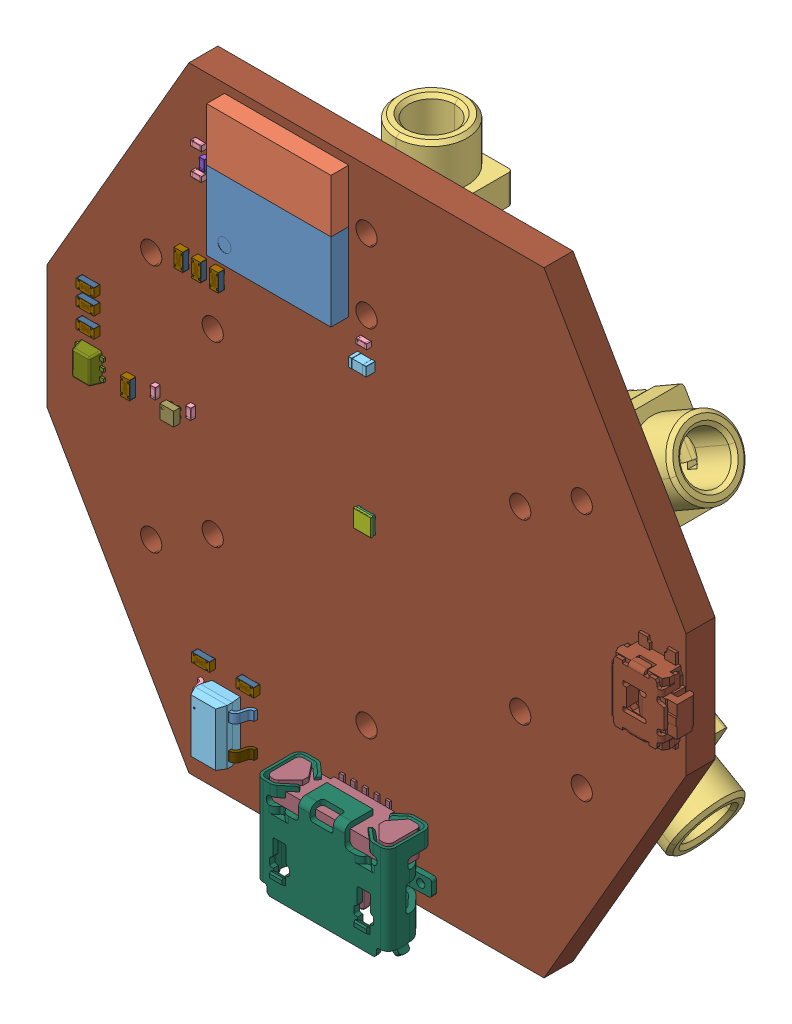
SolidWorks assembly Planter, configuration Default. Lengths in mm.
Overall size (36.62 36.63 8.42).
164 component instances, 47 part files, 0 mates.
Components (placement in the parent):
- U2-1: U2 [Default] at origin size (7 7.4 1)
  - U2-subassembly-1-1: U2-subassembly-1 [Default] at (-4.5 13.125 0) x (1 0 0) z (0 -1 0) size (7 1 7.4)
    - Murata MBN52832-1: Murata MBN52832 [Default] at origin size (7 1 4.4)
    - Murata MBN52832-1-1: Murata MBN52832-1 [Default] at origin size (7 1 3)
- J1-1: J1 [Default] at origin size (7.4 12.56 4.5)
  - CUI_DEVICES_SJ2-25103A-SMT-TR-1: CUI_DEVICES_SJ2-25103A-SMT-TR [Default] at (-0.2901 12.0599 -1.7307) x (0 1 0) z (0 0 -1) size (12.56 7.4 4.5)
- J3-1: J3 [Default] at origin size (14.57 12.69 4.5)
  - CUI_DEVICES_SJ2-25103A-SMT-TR-1: CUI_DEVICES_SJ2-25103A-SMT-TR [Default] at (10.5892 -5.7787 -1.7307) x (0.866025 -0.5 0) z (0 0 -1) size (12.56 7.4 4.5)
- J4-1: J4 [Default] at origin size (7.4 12.56 4.5)
  - CUI_DEVICES_SJ2-25103A-SMT-TR-1: CUI_DEVICES_SJ2-25103A-SMT-TR [Default] at (0.2901 -12.0599 -1.7307) x (0 -1 0) z (0 0 -1) size (12.56 7.4 4.5)
- J5-1: J5 [Default] at origin size (14.57 12.69 4.5)
  - CUI_DEVICES_SJ2-25103A-SMT-TR-1: CUI_DEVICES_SJ2-25103A-SMT-TR [Default] at (-10.2991 -6.2812 -1.7307) x (-0.866025 -0.5 0) z (0 0 -1) size (12.56 7.4 4.5)
- J6-1: J6 [Default] at origin size (14.57 12.69 4.5)
  - CUI_DEVICES_SJ2-25103A-SMT-TR-1: CUI_DEVICES_SJ2-25103A-SMT-TR [Default] at (-10.5892 5.7787 -1.7307) x (-0.866025 0.5 0) z (0 0 -1) size (12.56 7.4 4.5)
- C1-1: C1 [Default] at origin size (0.53 0.7 0.46)
  - CAP 0201-1: CAP 0201 [Default] at (-9.7499 0.5099 0) x (1 0 0) z (0 -1 0) size (0.53 0.46 0.7)
- C2-1: C2 [Default] at origin size (0.53 0.7 0.46)
  - CAP 0201-1: CAP 0201 [Default] at (-11.7499 0.5099 0) x (1 0 0) z (0 -1 0) size (0.53 0.46 0.7)
- C3-1: C3 [Default] at origin size (0.7 0.53 0.46)
  - CAP 0201-1: CAP 0201 [Default] at (-9.3101 12.2499 0) x (0 -1 0) z (-1 0 0) size (0.53 0.46 0.7)
- C4-1: C4 [Default] at origin size (0.7 0.53 0.46)
  - CAP 0201-1: CAP 0201 [Default] at (-9.3101 13.7499 0) x (0 -1 0) z (-1 0 0) size (0.53 0.46 0.7)
- C5-1: C5 [Default] at origin size (1 0.52 0.52)
  - 0402 cap-1: 0402 cap [Default] at (-0.0001 7.7499 0) x (-1 0 0) z (0 1 0) size (1 0.52 0.52)
- C6-1: C6 [Default] at origin size (0.7 0.53 0.46)
  - CAP 0201-1: CAP 0201 [Default] at (-0.0001 8.7499 0) x (0 -1 0) z (-1 0 0) size (0.53 0.46 0.7)
- D1-1: D1 [Default] at origin size (1.01 1.01 0.26)
  - LUMEX 0404 Base RGB-1: LUMEX 0404 Base RGB [Default] x (0 -1 0) z (0 0 1) size (1.01 1.01 0.15)
  - LUMEX 0404 Lens RGB-1: LUMEX 0404 Lens RGB [Default] at (0 0 0) x (0 -1 0) z (0 0 1) size (1 1 0.12)
- J2-1: J2 [Default] at origin size (14.57 12.69 4.5)
  - CUI_DEVICES_SJ2-25103A-SMT-TR-1: CUI_DEVICES_SJ2-25103A-SMT-TR [Default] at (10.2991 6.2812 -1.7307) x (0.866025 0.5 0) z (0 0 -1) size (12.56 7.4 4.5)
- L1-1: L1 [Default] at origin size (0.53 0.7 0.46)
  - FER 0201-1: FER 0201 [Default] at (-9 13.0001 -0.01) x (1 0 0) z (0 -1 0) size (0.53 0.46 0.7)
- R5-1: R5 [Default] at origin size (1 0.5 0.35)
  - R5-subassembly-1-1: R5-subassembly-1 [Default] at (-6.5001 -11 0) x (1 0 0) z (0 -1 0) size (1 0.35 0.5)
    - 0402 resistor-1: 0402 resistor [Default] at origin size (1 0.35 0.5)
    - 0402 resistor-1-1: 0402 resistor-1 [Default] at origin size (0.96 0.31 0.5)
- R6-1: R6 [Default] at origin size (0.5 1 0.35)
  - R6-subassembly-1-1: R6-subassembly-1 [Default] at (-9.5 7.7499 0) x (0 1 0) z (1 0 0) size (1 0.35 0.5)
    - 0402 resistor-1: 0402 resistor [Default] at origin size (1 0.35 0.5)
    - 0402 resistor-1-1: 0402 resistor-1 [Default] at origin size (0.96 0.31 0.5)
- R7-1: R7 [Default] at origin size (0.5 1 0.35)
  - R7-subassembly-1-1: R7-subassembly-1 [Default] at (-8.5 7.7499 0) x (0 1 0) z (1 0 0) size (1 0.35 0.5)
    - 0402 resistor-1: 0402 resistor [Default] at origin size (1 0.35 0.5)
    - 0402 resistor-1-1: 0402 resistor-1 [Default] at origin size (0.96 0.31 0.5)
- S1-1: S1 [Default] at origin size (3.55 4.7 1.35)
  - User Library-EVQP7-JA-01P-1: User Library-EVQP7-JA-01P [Default] at (16.5128 0.0268 0) x (0 1 0) z (1 0 0) size (4.7 1.35 3.55)
- U1-1: U1 [Default] at origin size (0.77 0.77 0.56)
  - ST flip-chip4-1: ST flip-chip4 [Default] at (-10.75 0 0) x (0 -1 0) z (-1 0 0) size (0.77 0.56 0.77)
- J7-1: J7 [Default] at origin size (7.92 5.67 3.01)
  - Amphenol 10118192-1: Amphenol 10118192 [Default] at (-97.9992 -12.7205 -0.35) x (1 0 0) z (0 -1 0) size (7.92 3.01 5.67)
    - unnamed-1: unnamed [Default] at origin size (6.89 2.28 4.27)
    - unnamed-1-1: unnamed-1 [Default] at origin size (0 0.01 0)
    - unnamed-2-1: unnamed-2 [Default] at origin size (7.92 3.01 5.67)
- Q1-1: Q1 [Default] at origin size (1.6 1.6 0.6)
  - Diodes SOT-563-1: Diodes SOT-563 [Default] at (-15.5 0 0) x (0 1 0) z (0 0 1) size (1.6 1.6 0.6)
- R1-1: R1 [Default] at origin size (0.5 1 0.35)
  - R1-subassembly-1-1: R1-subassembly-1 [Default] at (-13 0.0001 0) x (0 -1 0) z (-1 0 0) size (1 0.35 0.5)
    - 0402 resistor-1: 0402 resistor [Default] at origin size (1 0.35 0.5)
    - 0402 resistor-1-1: 0402 resistor-1 [Default] at origin size (0.96 0.31 0.5)
- R2-1: R2 [Default] at origin size (1 0.5 0.35)
  - R2-subassembly-1-1: R2-subassembly-1 [Default] at (-15.4999 2.625 0) x (-1 0 0) z (0 1 0) size (1 0.35 0.5)
    - 0402 resistor-1: 0402 resistor [Default] at origin size (1 0.35 0.5)
    - 0402 resistor-1-1: 0402 resistor-1 [Default] at origin size (0.96 0.31 0.5)
- R3-1: R3 [Default] at origin size (1 0.5 0.35)
  - R3-subassembly-1-1: R3-subassembly-1 [Default] at (-15.4999 1.5 0) x (-1 0 0) z (0 1 0) size (1 0.35 0.5)
    - 0402 resistor-1: 0402 resistor [Default] at origin size (1 0.35 0.5)
    - 0402 resistor-1-1: 0402 resistor-1 [Default] at origin size (0.96 0.31 0.5)
- R4-1: R4 [Default] at origin size (1 0.5 0.35)
  - R4-subassembly-1-1: R4-subassembly-1 [Default] at (-15.5001 4 0) x (1 0 0) z (0 -1 0) size (1 0.35 0.5)
    - 0402 resistor-1: 0402 resistor [Default] at origin size (1 0.35 0.5)
    - 0402 resistor-1-1: 0402 resistor-1 [Default] at origin size (0.96 0.31 0.5)
- R8-1: R8 [Default] at origin size (0.5 1 0.35)
  - R8-subassembly-1-1: R8-subassembly-1 [Default] at (-10.5 7.7499 0) x (0 1 0) z (1 0 0) size (1 0.35 0.5)
    - 0402 resistor-1: 0402 resistor [Default] at origin size (1 0.35 0.5)
    - 0402 resistor-1-1: 0402 resistor-1 [Default] at origin size (0.96 0.31 0.5)
- R9-1: R9 [Default] at origin size (1 0.5 0.35)
  - R9-subassembly-1-1: R9-subassembly-1 [Default] at (-9.0001 -11 0) x (1 0 0) z (0 -1 0) size (1 0.35 0.5)
    - 0402 resistor-1: 0402 resistor [Default] at origin size (1 0.35 0.5)
    - 0402 resistor-1-1: 0402 resistor-1 [Default] at origin size (0.96 0.31 0.5)
- U3-1: U3 [Default] at origin size (3.2 3.11 1.46)
  - U3-subassembly-1-1: U3-subassembly-1 [Default] at (-7.75 -13.5 0) x (1 0 0) z (0 0 1) size (3.2 3.11 1.46)
    - Microchip SOT-23-5-1: Microchip SOT-23-5 [Default] at origin size (0.11 0.11 0.02)
    - Microchip SOT-23-5-1-1: Microchip SOT-23-5-1 [Default] at origin size (0.7 0.51 0.93)
    - Microchip SOT-23-5-2-1: Microchip SOT-23-5-2 [Default] at origin size (0.7 0.51 0.93)
    - Microchip SOT-23-5-3-1: Microchip SOT-23-5-3 [Default] at origin size (0.7 0.51 0.93)
    - Microchip SOT-23-5-4-1: Microchip SOT-23-5-4 [Default] at origin size (0.7 0.51 0.93)
    - Microchip SOT-23-5-5-1: Microchip SOT-23-5-5 [Default] at origin size (0.7 0.51 0.93)
    - Microchip SOT-23-5-6-1: Microchip SOT-23-5-6 [Default] at origin size (1.81 3.11 1.3)
- R10-1: R10 [Default] at origin size (0.93 1.12 0.35)
  - R10-subassembly-1-1: R10-subassembly-1 [Default] at (-4.2164 4.125 -1.6307) x (-0.5 -0.866025 0) z (0.866025 -0.5 0) size (1 0.35 0.5)
    - 0402 resistor-1: 0402 resistor [Default] at origin size (1 0.35 0.5)
    - 0402 resistor-1-1: 0402 resistor-1 [Default] at origin size (0.96 0.31 0.5)
- R11-1: R11 [Default] at origin size (0.93 1.12 0.35)
  - R11-subassembly-1-1: R11-subassembly-1 [Default] at (-5.2836 1.375 -1.6307) x (0.5 0.866025 0) z (-0.866025 0.5 0) size (1 0.35 0.5)
    - 0402 resistor-1: 0402 resistor [Default] at origin size (1 0.35 0.5)
    - 0402 resistor-1-1: 0402 resistor-1 [Default] at origin size (0.96 0.31 0.5)
- R12-1: R12 [Default] at origin size (0.93 1.12 0.35)
  - R12-subassembly-1-1: R12-subassembly-1 [Default] at (-5.679 -1.6229 -1.6307) x (0.5 -0.866025 0) z (0.866025 0.5 0) size (1 0.35 0.5)
    - 0402 resistor-1: 0402 resistor [Default] at origin size (1 0.35 0.5)
    - 0402 resistor-1-1: 0402 resistor-1 [Default] at origin size (0.96 0.31 0.5)
- R13-1: R13 [Default] at origin size (0.93 1.12 0.35)
  - R13-subassembly-1-1: R13-subassembly-1 [Default] at (-3.821 -3.8771 -1.6307) x (-0.5 0.866025 0) z (-0.866025 -0.5 0) size (1 0.35 0.5)
    - 0402 resistor-1: 0402 resistor [Default] at origin size (1 0.35 0.5)
    - 0402 resistor-1-1: 0402 resistor-1 [Default] at origin size (0.96 0.31 0.5)
- R14-1: R14 [Default] at origin size (1 0.5 0.35)
  - R14-subassembly-1-1: R14-subassembly-1 [Default] at (-1.4251 -5.7499 -1.6307) x (1 0 0) z (0 1 0) size (1 0.35 0.5)
    - 0402 resistor-1: 0402 resistor [Default] at origin size (1 0.35 0.5)
    - 0402 resistor-1-1: 0402 resistor-1 [Default] at origin size (0.96 0.31 0.5)
- R15-1: R15 [Default] at origin size (1 0.5 0.35)
  - R15-subassembly-1-1: R15-subassembly-1 [Default] at (1.4251 -5.25 -1.6307) x (-1 0 0) z (0 -1 0) size (1 0.35 0.5)
    - 0402 resistor-1: 0402 resistor [Default] at origin size (1 0.35 0.5)
    - 0402 resistor-1-1: 0402 resistor-1 [Default] at origin size (0.96 0.31 0.5)
- R16-1: R16 [Default] at origin size (0.93 1.12 0.35)
  - R16-subassembly-1-1: R16-subassembly-1 [Default] at (4.2539 -4.1271 -1.6307) x (0.5 0.866025 0) z (-0.866025 0.5 0) size (1 0.35 0.5)
    - 0402 resistor-1: 0402 resistor [Default] at origin size (1 0.35 0.5)
    - 0402 resistor-1-1: 0402 resistor-1 [Default] at origin size (0.96 0.31 0.5)
- R17-1: R17 [Default] at origin size (0.93 1.12 0.35)
  - R17-subassembly-1-1: R17-subassembly-1 [Default] at (5.2461 -1.3729 -1.6307) x (-0.5 -0.866025 0) z (0.866025 -0.5 0) size (1 0.35 0.5)
    - 0402 resistor-1: 0402 resistor [Default] at origin size (1 0.35 0.5)
    - 0402 resistor-1-1: 0402 resistor-1 [Default] at origin size (0.96 0.31 0.5)
- R18-1: R18 [Default] at origin size (0.93 1.12 0.35)
  - R18-subassembly-1-1: R18-subassembly-1 [Default] at (5.679 1.6229 -1.6307) x (-0.5 0.866025 0) z (-0.866025 -0.5 0) size (1 0.35 0.5)
    - 0402 resistor-1: 0402 resistor [Default] at origin size (1 0.35 0.5)
    - 0402 resistor-1-1: 0402 resistor-1 [Default] at origin size (0.96 0.31 0.5)
- R19-1: R19 [Default] at origin size (0.93 1.12 0.35)
  - R19-subassembly-1-1: R19-subassembly-1 [Default] at (3.821 3.8771 -1.6307) x (0.5 -0.866025 0) z (0.866025 0.5 0) size (1 0.35 0.5)
    - 0402 resistor-1: 0402 resistor [Default] at origin size (1 0.35 0.5)
    - 0402 resistor-1-1: 0402 resistor-1 [Default] at origin size (0.96 0.31 0.5)
- R20-1: R20 [Default] at origin size (1 0.5 0.35)
  - R20-subassembly-1-1: R20-subassembly-1 [Default] at (1.4251 5.75 -1.6307) x (-1 0 0) z (0 -1 0) size (1 0.35 0.5)
    - 0402 resistor-1: 0402 resistor [Default] at origin size (1 0.35 0.5)
    - 0402 resistor-1-1: 0402 resistor-1 [Default] at origin size (0.96 0.31 0.5)
- R21-1: R21 [Default] at origin size (1 0.5 0.35)
  - R21-subassembly-1-1: R21-subassembly-1 [Default] at (-1.4251 5.25 -1.6307) x (1 0 0) z (0 1 0) size (1 0.35 0.5)
    - 0402 resistor-1: 0402 resistor [Default] at origin size (1 0.35 0.5)
    - 0402 resistor-1-1: 0402 resistor-1 [Default] at origin size (0.96 0.31 0.5)
- U4-1: U4 [Default] at origin size (3.1 3.1 0.84)
  - U4-subassembly-1-1: U4-subassembly-1 [Default] at (0.0001 0 -1.6307) x (0 1 0) z (0 0 -1) size (3.1 3.1 0.84)
    - VQFN20_3X3_MCH-1: VQFN20_3X3_MCH [Default] at origin size (1.7 1.7 0.05)
    - VQFN20_3X3_MCH-1-1: VQFN20_3X3_MCH-1 [Default] at origin size (0.28 0.41 0.05)
    - VQFN20_3X3_MCH-2-1: VQFN20_3X3_MCH-2 [Default] at origin size (0.28 0.41 0.05)
    - VQFN20_3X3_MCH-3-1: VQFN20_3X3_MCH-3 [Default] at origin size (0.28 0.41 0.05)
    - VQFN20_3X3_MCH-4-1: VQFN20_3X3_MCH-4 [Default] at origin size (0.28 0.41 0.05)
    - VQFN20_3X3_MCH-5-1: VQFN20_3X3_MCH-5 [Default] at origin size (0.28 0.41 0.05)
    - VQFN20_3X3_MCH-6-1: VQFN20_3X3_MCH-6 [Default] at origin size (0.41 0.28 0.05)
    - VQFN20_3X3_MCH-7-1: VQFN20_3X3_MCH-7 [Default] at origin size (0.41 0.28 0.05)
    - VQFN20_3X3_MCH-8-1: VQFN20_3X3_MCH-8 [Default] at origin size (0.41 0.28 0.05)
    - VQFN20_3X3_MCH-9-1: VQFN20_3X3_MCH-9 [Default] at origin size (0.41 0.28 0.05)
    - VQFN20_3X3_MCH-10-1: VQFN20_3X3_MCH-10 [Default] at origin size (0.41 0.28 0.05)
    - VQFN20_3X3_MCH-11-1: VQFN20_3X3_MCH-11 [Default] at origin size (0.28 0.41 0.05)
    - VQFN20_3X3_MCH-12-1: VQFN20_3X3_MCH-12 [Default] at origin size (0.28 0.41 0.05)
    - VQFN20_3X3_MCH-13-1: VQFN20_3X3_MCH-13 [Default] at origin size (0.28 0.41 0.05)
    - VQFN20_3X3_MCH-14-1: VQFN20_3X3_MCH-14 [Default] at origin size (0.28 0.41 0.05)
    - VQFN20_3X3_MCH-15-1: VQFN20_3X3_MCH-15 [Default] at origin size (0.28 0.41 0.05)
    - VQFN20_3X3_MCH-16-1: VQFN20_3X3_MCH-16 [Default] at origin size (0.41 0.28 0.05)
    - VQFN20_3X3_MCH-17-1: VQFN20_3X3_MCH-17 [Default] at origin size (0.41 0.28 0.05)
    - VQFN20_3X3_MCH-18-1: VQFN20_3X3_MCH-18 [Default] at origin size (0.41 0.28 0.05)
    - VQFN20_3X3_MCH-19-1: VQFN20_3X3_MCH-19 [Default] at origin size (0.41 0.28 0.05)
    - VQFN20_3X3_MCH-20-1: VQFN20_3X3_MCH-20 [Default] at origin size (0.41 0.28 0.05)
    - VQFN20_3X3_MCH-21-1: VQFN20_3X3_MCH-21 [Default] at origin size (3.1 3.1 0.79)
    - VQFN20_3X3_MCH-22-1: VQFN20_3X3_MCH-22 [Default] at origin size (0.15 0.15 0)
- Board-1: Board [Default] at origin size (36 34.64 1.63)
  - Board-Part-1-1: Board-Part-1 [Default] at (0 0 -1.6307) size (36 34.64 1.63)
